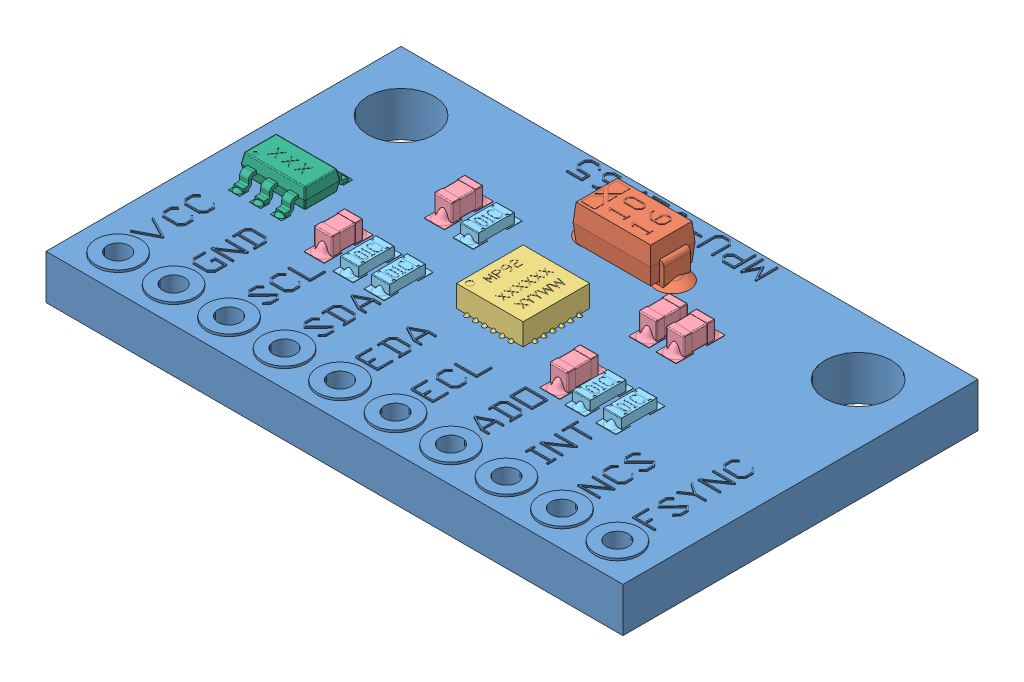
SolidWorks assembly MPU9250, configuration Predeterminado. Lengths in mm.
Overall size (26 3.91 16).
14 component instances, 6 part files, 49 mates.
Components (placement in the parent):
- PCB-1: PCB [Predeterminado] at (-2.9998 1.0768 26) size (26 2.2 16)
- C2-1: C2 [Predeterminado] at (-2.4989 2.0768 21) x (0 0 -1) z (1 0 0) size (2 1.88 5)
- MP92-1: MP92 [Predeterminado] at (-2.9998 1.0968 25.5) x (0 0 -1) z (1 0 0) size (3.29 2.13 3.29)
- C1-1: C1 [Predeterminado<Como mecanizada>] at (2.1384 1.0968 23.0905) x (0 0 1) z (-1 0 0) size (2.2 0.84 0.9)
- C1-2: C1 [Predeterminado<Como mecanizada>] at (0.9102 1.0968 27.1044) x (0 0 1) z (-1 0 0) size (2.2 0.84 0.9)
- C1-3: C1 [Predeterminado<Como mecanizada>] at (0.9102 1.0968 23.0905) x (0 0 1) z (-1 0 0) size (2.2 0.84 0.9)
- C1-4: C1 [Predeterminado<Como mecanizada>] at (-8.3098 1.0968 23.0905) x (0 0 1) z (-1 0 0) size (2.2 0.84 0.9)
- C1-5: C1 [Predeterminado<Como mecanizada>] at (-9.7098 1.0968 27.1044) x (0 0 1) z (-1 0 0) size (2.2 0.84 0.9)
- R1-1: R1 [Predeterminado] at (3.5484 1.1168 27.2144) x (0 0 -1) z (1 0 0) size (2.2 0.47 0.9)
- R1-2: R1 [Predeterminado] at (2.1484 1.1168 27.2144) x (0 0 -1) z (1 0 0) size (2.2 0.47 0.9)
- R1-3: R1 [Predeterminado] at (-6.8998 1.1168 23.2005) x (0 0 -1) z (1 0 0) size (2.2 0.47 0.9)
- R1-4: R1 [Predeterminado] at (-8.2998 1.1168 27.2144) x (0 0 -1) z (1 0 0) size (2.2 0.47 0.9)
- R1-5: R1 [Predeterminado] at (-6.8998 1.1168 27.2144) x (0 0 -1) z (1 0 0) size (2.2 0.47 0.9)
- V1-1: V1 [Predeterminado] at (-13.0785 1.5868 25.9) size (2.9 0.96 3.2)
Mates (geometry in assembly coordinates):
- Coincidente1: coincident anti-aligned: plane of PCB-1 through (-2.9998 1.0768 26) normal (0 1 0); plane of C2-1 through (-4.2489 1.0768 21.6) normal (0 -1 0)
- Paralelo1: parallel anti-aligned: line of PCB-1 through (-15.9998 1.0768 18) axis (1 0 0); line of C2-1 through (-0.7489 2.0768 20) axis (-1 0 0)
- Distancia2: distance = 4 mm: plane of PCB-1 through (-2.9998 -0.9232 18) normal (0 0 -1); line of C2-1 through (-4.2489 2.0768 22) axis (1 0 0)
- Distancia3: distance = 15 mm: line of PCB-1 through (10.0002 1.0768 34) axis (0 0 -1); moEndPointRef_w of C2-1
- Paralelo2: parallel aligned: plane of PCB-1 through (-15.9998 -0.9232 26) normal (-1 0 0); plane of MP92-1 through (-4.4998 2.0768 27) normal (-1 0 0)
- Coincidente3: coincident anti-aligned: plane of PCB-1 through (-2.9998 1.0768 26) normal (0 1 0); plane of MP92-1 through (-4.078 1.0768 23.8942) normal (0 -1 0)
- Distancia4: distance = 9 mm anti-aligned: plane of MP92-1 through (-2.9998 1.2268 27) normal (0 0 1); plane of PCB-1 through (-2.9998 -0.9232 18) normal (0 0 -1)
- Distancia5: distance = 14.5 mm anti-aligned: plane of MP92-1 through (-1.4998 2.0768 27) normal (1 0 0); plane of PCB-1 through (-15.9998 -0.9232 26) normal (-1 0 0)
- Coincidente4: coincident anti-aligned: plane of PCB-1 through (-2.9998 1.0768 26) normal (0 1 0); plane of C1-2 through (0.9102 1.0768 27.1044) normal (0 -1 0)
- Coincidente5: coincident anti-aligned: plane of PCB-1 through (-2.9998 1.0768 26) normal (0 1 0); plane of C1-4 through (-8.3098 1.0768 23.0905) normal (0 -1 0)
- Coincidente6: coincident anti-aligned: plane of PCB-1 through (-2.9998 1.0768 26) normal (0 1 0); plane of C1-5 through (-9.7098 1.0768 27.1044) normal (0 -1 0)
- Coincidente7: coincident anti-aligned: plane of PCB-1 through (-2.9998 1.0768 26) normal (0 1 0); plane of C1-3 through (0.9102 1.0768 23.0905) normal (0 -1 0)
- Coincidente8: coincident anti-aligned: plane of PCB-1 through (-2.9998 1.0768 26) normal (0 1 0); plane of C1-1 through (2.1384 1.0768 23.0905) normal (0 -1 0)
- Paralelo3: parallel anti-aligned: plane of PCB-1 through (10.0002 -0.9232 26) normal (1 0 0); plane of C1-3 through (0.5102 1.8968 22.7405) normal (-1 0 0)
- Paralelo4: parallel anti-aligned: plane of PCB-1 through (10.0002 -0.9232 26) normal (1 0 0); plane of C1-1 through (1.7384 1.8968 22.7405) normal (-1 0 0)
- Paralelo5: parallel anti-aligned: plane of PCB-1 through (10.0002 -0.9232 26) normal (1 0 0); plane of C1-4 through (-8.7098 1.8968 22.7405) normal (-1 0 0)
- Paralelo6: parallel anti-aligned: plane of PCB-1 through (10.0002 -0.9232 26) normal (1 0 0); plane of C1-5 through (-10.1098 1.8968 26.7544) normal (-1 0 0)
- Paralelo7: parallel anti-aligned: plane of PCB-1 through (10.0002 -0.9232 26) normal (1 0 0); plane of C1-2 through (0.5102 1.8968 26.7544) normal (-1 0 0)
- Coincidente15: coincident aligned: plane of C1-1 through (2.1384 1.0968 23.7905) normal (0 0 1); plane of C1-3 through (0.9102 1.0968 23.7905) normal (0 0 1)
- Coincidente16: coincident aligned: plane of C1-2 through (0.5102 1.8968 26.7544) normal (-1 0 0); plane of C1-3 through (0.5102 1.8968 22.7405) normal (-1 0 0)
- Coincidente17: coincident anti-aligned: plane of PCB-1 through (-2.9998 1.0768 26) normal (0 1 0); plane of R1-4 through (-8.2998 1.0768 27.2144) normal (0 -1 0)
- Coincidente18: coincident anti-aligned: plane of PCB-1 through (-2.9998 1.0768 26) normal (0 1 0); plane of R1-5 through (-6.8998 1.0768 27.2144) normal (0 -1 0)
- Coincidente19: coincident anti-aligned: plane of PCB-1 through (-2.9998 1.0768 26) normal (0 1 0); plane of R1-3 through (-6.8998 1.0768 23.2005) normal (0 -1 0)
- Coincidente20: coincident anti-aligned: plane of PCB-1 through (-2.9998 1.0768 26) normal (0 1 0); plane of R1-1 through (3.5484 1.0768 27.2144) normal (0 -1 0)
- Coincidente21: coincident anti-aligned: plane of PCB-1 through (-2.9998 1.0768 26) normal (0 1 0); plane of R1-2 through (2.1484 1.0768 27.2144) normal (0 -1 0)
- Paralelo8: parallel aligned: plane of PCB-1 through (10.0002 -0.9232 26) normal (1 0 0); plane of R1-2 through (2.5484 1.5468 28.0144) normal (1 0 0)
- Paralelo9: parallel anti-aligned: plane of PCB-1 through (-15.9998 -0.9232 26) normal (-1 0 0); plane of R1-1 through (3.9484 1.5468 28.0144) normal (1 0 0)
- Paralelo10: parallel anti-aligned: plane of PCB-1 through (-15.9998 -0.9232 26) normal (-1 0 0); plane of R1-5 through (-6.4998 1.5468 28.0144) normal (1 0 0)
- Paralelo11: parallel anti-aligned: plane of PCB-1 through (-15.9998 -0.9232 26) normal (-1 0 0); plane of R1-3 through (-6.4998 1.5468 24.0005) normal (1 0 0)
- Paralelo12: parallel anti-aligned: plane of PCB-1 through (-15.9998 -0.9232 26) normal (-1 0 0); plane of R1-4 through (-7.8998 1.5468 28.0144) normal (1 0 0)
- Coincidente28: coincident aligned: plane of C1-2 through (0.9102 1.0968 26.4044) normal (0 0 -1); plane of R1-2 through (2.5484 1.5168 26.4044) normal (0 0 -1)
- Coincidente29: coincident aligned: plane of R1-1 through (3.9484 1.5168 26.4044) normal (0 0 -1); plane of R1-2 through (2.5484 1.5168 26.4044) normal (0 0 -1)
- Coincidente30: coincident aligned: plane of C1-5 through (-9.7098 1.0968 26.4044) normal (0 0 -1); plane of R1-4 through (-7.8998 1.5168 26.4044) normal (0 0 -1)
- Coincidente31: coincident aligned: plane of R1-4 through (-7.8998 1.5168 26.4044) normal (0 0 -1); plane of R1-5 through (-6.4998 1.5168 26.4044) normal (0 0 -1)
- Coincidente32: coincident aligned: plane of C1-2 through (0.9102 1.0968 26.4044) normal (0 0 -1); plane of R1-5 through (-6.4998 1.5168 26.4044) normal (0 0 -1)
- Coincidente35: coincident aligned: plane of C1-3 through (0.9102 1.0968 22.3905) normal (0 0 -1); plane of C1-4 through (-8.3098 1.0968 22.3905) normal (0 0 -1)
- Coincidente36: coincident aligned: plane of C1-4 through (-8.3098 1.0968 22.3905) normal (0 0 -1); plane of R1-3 through (-6.4998 1.5168 22.3905) normal (0 0 -1)
- Coincidente37: coincident aligned: plane of R1-3 through (-6.4998 1.5468 24.0005) normal (1 0 0); plane of R1-5 through (-6.4998 1.5468 28.0144) normal (1 0 0)
- Coincidente38: coincident aligned: plane of C1-4 through (-7.8998 1.0868 23.7905) normal (1 0 0); plane of R1-4 through (-7.8998 1.5468 28.0144) normal (1 0 0)
- Coincidente40: coincident aligned: plane of C1-1 through (2.5484 1.0868 22.3905) normal (1 0 0); plane of R1-2 through (2.5484 1.5468 28.0144) normal (1 0 0)
- Distancia6: distance = 9.5 mm anti-aligned: plane of C1-3 through (0.5002 1.0868 22.3905) normal (-1 0 0); plane of PCB-1 through (10.0002 -0.9232 26) normal (1 0 0)
- Distancia8: distance = 2.2 mm anti-aligned: plane of R1-2 through (1.7484 1.5468 28.0144) normal (-1 0 0); plane of R1-1 through (3.9484 1.5468 28.0144) normal (1 0 0)
- Distancia9: distance = 9.5 mm anti-aligned: plane of R1-5 through (-6.4998 1.5468 28.0144) normal (1 0 0); plane of PCB-1 through (-15.9998 -0.9232 26) normal (-1 0 0)
- Distancia10: distance = 2.2 mm anti-aligned: plane of R1-5 through (-6.4998 1.5468 28.0144) normal (1 0 0); plane of R1-4 through (-8.6998 1.5468 28.0144) normal (-1 0 0)
- Distancia11: distance = 2.2 mm anti-aligned: plane of C1-5 through (-10.1098 1.8968 26.7544) normal (-1 0 0); plane of C1-4 through (-7.9098 1.8968 22.7405) normal (1 0 0)
- Coincidente49: coincident: plane of PCB-1 through (-2.9998 1.0768 26) normal (0 1 0); plane of V1-1 through (-14.0285 1.0768 25.9) normal (0 -1 0)
- Paralelo14: parallel: plane of PCB-1 through (-15.9998 -0.9232 26) normal (-1 0 0); plane of V1-1 through (-14.2285 1.5118 24.975) normal (-1 0 0)
- Distancia12: distance = 4.25 mm: line of V1-1 through (-11.7498 2.0368 26.5787) axis (0 0 -1); plane of PCB-1 through (-15.9998 -0.9232 26) normal (-1 0 0)
- Distancia13: distance = 9.5 mm: plane of PCB-1 through (-2.9998 -0.9232 18) normal (0 0 -1); line of V1-1 through (-13.7785 1.0868 27.5) axis (-1 0 0)
